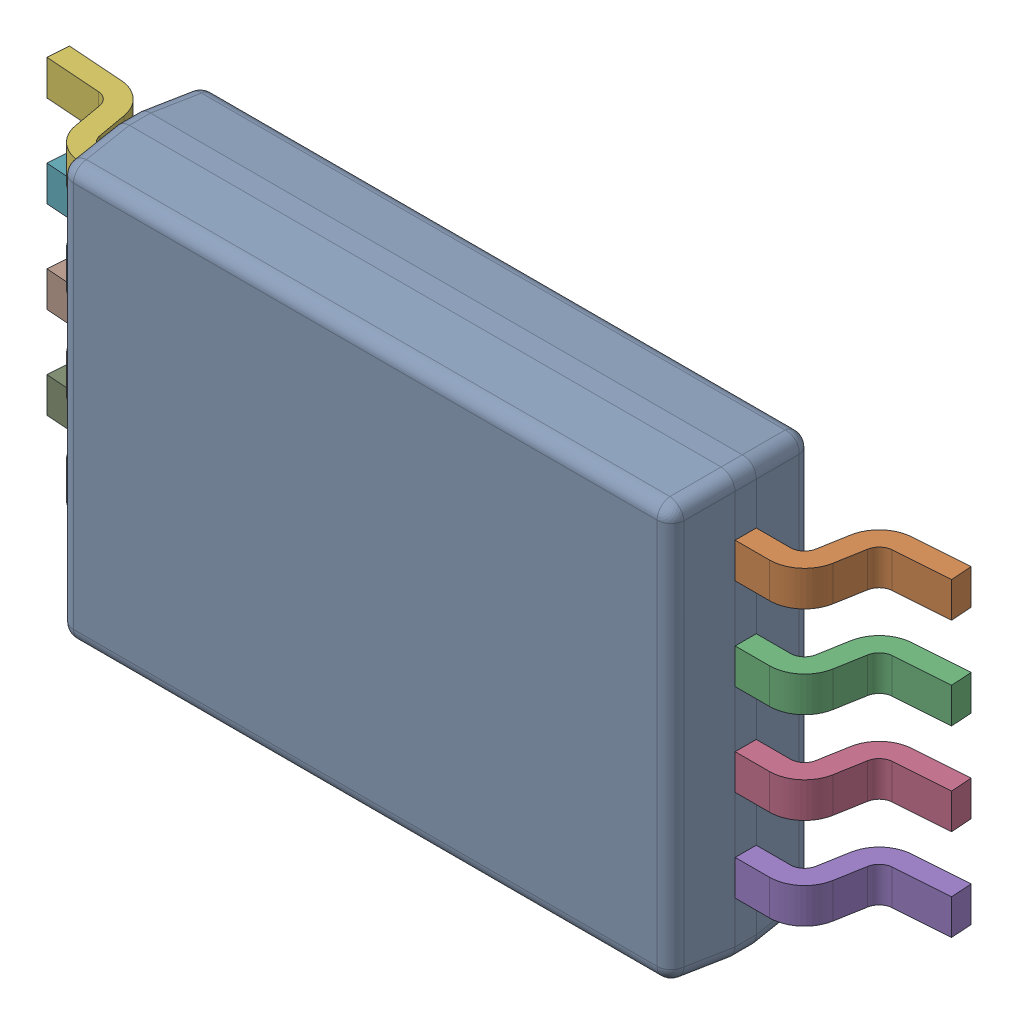
SolidWorks assembly U15, configuration ﾃﾞﾌｫﾙﾄ. Lengths in mm.
Overall size (6.42 3 1.12).
10 component instances, 2 part files, 0 mates.
Components (placement in the parent):
- PW0008A-1: PW0008A [ﾃﾞﾌｫﾙﾄ] at (53.4 16 0.65) x (0 1 0) z (1 0 0) size (3 1.12 6.42)
  - BODY-SO-1: BODY-SO [ﾃﾞﾌｫﾙﾄ] at origin size (3 1.03 4.4)
  - LEAD-SO-1: LEAD-SO [ﾃﾞﾌｫﾙﾄ] at (0.975 -0.425 2.575) size (0.25 0.68 1.01)
  - LEAD-SO-2: LEAD-SO [ﾃﾞﾌｫﾙﾄ] at (0.325 -0.425 2.575) size (0.25 0.68 1.01)
  - LEAD-SO-3: LEAD-SO [ﾃﾞﾌｫﾙﾄ] at (-0.325 -0.425 2.575) size (0.25 0.68 1.01)
  - LEAD-SO-4: LEAD-SO [ﾃﾞﾌｫﾙﾄ] at (-0.975 -0.425 2.575) size (0.25 0.68 1.01)
  - LEAD-SO-5: LEAD-SO [ﾃﾞﾌｫﾙﾄ] at (0.975 -0.425 -2.575) x (-1 0 0) z (0 0 -1) size (0.25 0.68 1.01)
  - LEAD-SO-6: LEAD-SO [ﾃﾞﾌｫﾙﾄ] at (0.325 -0.425 -2.575) x (-1 0 0) z (0 0 -1) size (0.25 0.68 1.01)
  - LEAD-SO-7: LEAD-SO [ﾃﾞﾌｫﾙﾄ] at (-0.325 -0.425 -2.575) x (-1 0 0) z (0 0 -1) size (0.25 0.68 1.01)
  - LEAD-SO-8: LEAD-SO [ﾃﾞﾌｫﾙﾄ] at (-0.975 -0.425 -2.575) x (-1 0 0) z (0 0 -1) size (0.25 0.68 1.01)
